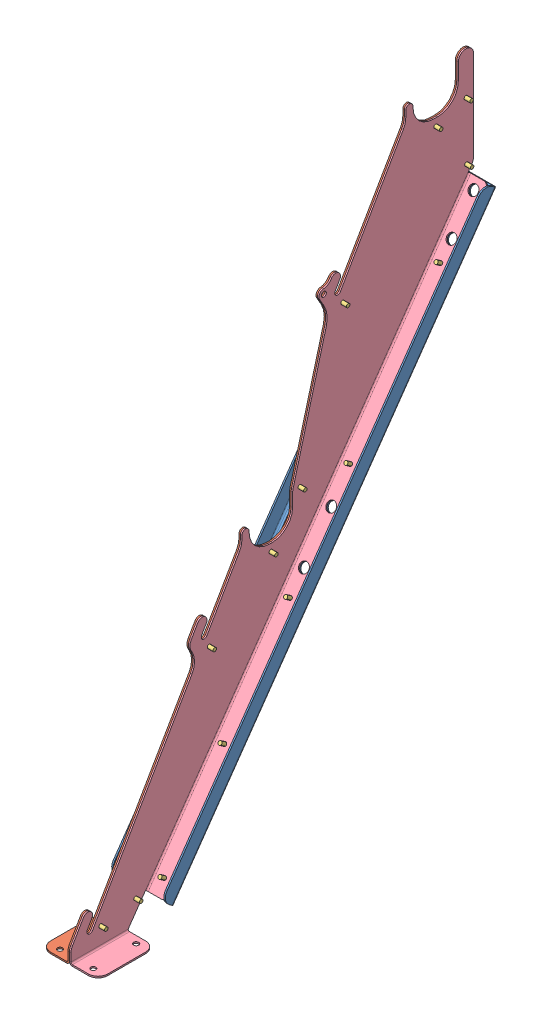
SolidWorks assembly GE-22352, configuration Default. Lengths in mm.
Overall size (76.2 794.54 536.39).
22 component instances, 4 part files, 13 mates.
Components (placement in the parent):
- GE-22352-03-1: GE-22352-03 [Default] at (0 34.7235 -102.5797) x (1 0 0) z (0 0.573576 0.819152) size (71.44 749.3 21.03)
- GE-22352-01-2: GE-22352-01 [GE-22352-01] at (-1.9844 3.9688 -76.2) x (-1 0 0) z (0 0 -1) size (38.1 794.54 536.39)
- rivet_.1875_.126-.25-3: rivet_.1875_.126-.25 [Default] at (-1.9844 738.1875 -526.1657) x (0 -0.615663 -0.788009) z (-1 0 0) size (10.01 10.01 13.03)
- rivet_.1875_.126-.25-4: rivet_.1875_.126-.25 [Default] at (-14.6844 402.9 -362.8021) x (-0.959679 -0.230262 0.161231) z (0 -0.573576 -0.819152) size (10.01 10.01 13.03)
- rivet_.1875_.126-.25-15: rivet_.1875_.126-.25 [Default] at (14.6844 574.5533 -482.995) x (-0.959679 -0.230262 0.161231) z (0 -0.573576 -0.819152) size (10.01 10.01 13.03)
- rivet_.1875_.126-.25-18: rivet_.1875_.126-.25 [Default] at (14.6844 49.1902 -115.1318) x (-0.959679 -0.230262 0.161231) z (0 -0.573576 -0.819152) size (10.01 10.01 13.03)
- rivet_.1875_.126-.25-19: rivet_.1875_.126-.25 [Default] at (14.6844 402.9 -362.8021) x (-0.959679 -0.230262 0.161231) z (0 -0.573576 -0.819152) size (10.01 10.01 13.03)
- rivet_.1875_.126-.25-20: rivet_.1875_.126-.25 [Default] at (-14.6844 288.4645 -282.6735) x (-0.959679 -0.230262 0.161231) z (0 -0.573576 -0.819152) size (10.01 10.01 13.03)
- rivet_.1875_.126-.25-21: rivet_.1875_.126-.25 [Default] at (14.6844 288.4645 -282.6735) x (-0.959679 -0.230262 0.161231) z (0 -0.573576 -0.819152) size (10.01 10.01 13.03)
- rivet_.1875_.126-.25-22: rivet_.1875_.126-.25 [Default] at (-14.6844 163.6257 -195.2604) x (-0.959679 -0.230262 0.161231) z (0 -0.573576 -0.819152) size (10.01 10.01 13.03)
- rivet_.1875_.126-.25-23: rivet_.1875_.126-.25 [Default] at (14.6844 163.6257 -195.2604) x (-0.959679 -0.230262 0.161231) z (0 -0.573576 -0.819152) size (10.01 10.01 13.03)
- rivet_.1875_.126-.25-24: rivet_.1875_.126-.25 [Default] at (-14.6844 49.1902 -115.1318) x (-0.959679 -0.230262 0.161231) z (0 -0.573576 -0.819152) size (10.01 10.01 13.03)
- GE-22352-02-4: GE-22352-02 [GE-22352-02] at (1.9844 3.9688 -76.2) size (38.1 794.54 536.39)
- rivet_.1875_.126-.25-33: rivet_.1875_.126-.25 [Default] at (-14.6844 574.5533 -482.995) x (-0.959679 -0.230262 0.161231) z (0 -0.573576 -0.819152) size (10.01 10.01 13.03)
- rivet_.1875_.126-.25-34: rivet_.1875_.126-.25 [Default] at (-1.9844 25.9658 -39.5735) x (0 -0.615663 -0.788009) z (-1 0 0) size (10.01 10.01 13.03)
- rivet_.1875_.126-.25-35: rivet_.1875_.126-.25 [Default] at (-1.9844 34.6608 -86.0629) x (0 -0.615663 -0.788009) z (-1 0 0) size (10.01 10.01 13.03)
- rivet_.1875_.126-.25-36: rivet_.1875_.126-.25 [Default] at (-1.9844 276.1822 -184.036) x (0 -0.615663 -0.788009) z (-1 0 0) size (10.01 10.01 13.03)
- rivet_.1875_.126-.25-37: rivet_.1875_.126-.25 [Default] at (-1.9844 344.4875 -266.3031) x (0 -0.615663 -0.788009) z (-1 0 0) size (10.01 10.01 13.03)
- rivet_.1875_.126-.25-38: rivet_.1875_.126-.25 [Default] at (-1.9844 400.05 -304.8) x (0 -0.615663 -0.788009) z (-1 0 0) size (10.01 10.01 13.03)
- rivet_.1875_.126-.25-39: rivet_.1875_.126-.25 [Default] at (-1.9844 584.1408 -361.836) x (0 -0.615663 -0.788009) z (-1 0 0) size (10.01 10.01 13.03)
- rivet_.1875_.126-.25-40: rivet_.1875_.126-.25 [Default] at (-1.9844 661.1938 -526.8689) x (0 -0.615663 -0.788009) z (-1 0 0) size (10.01 10.01 13.03)
- rivet_.1875_.126-.25-41: rivet_.1875_.126-.25 [Default] at (-1.9844 725.4875 -485.775) x (0 -0.615663 -0.788009) z (-1 0 0) size (10.01 10.01 13.03)
Mates (geometry in assembly coordinates):
- Concentric61: concentric aligned: cylinder of updated low funnel vertical_leftright-2 through (-1.9844 738.1875 -526.1657) axis (-1 0 0) radius 2.4574; cylinder of rivet_.1875_.126-.25-3 through (9.4456 738.1875 -526.1657) axis (-1 0 0) radius 2.3813
- Coincident41: coincident anti-aligned: plane of updated low funnel vertical_leftright-2 through (-1.9844 3.9688 -76.2) normal (-1 0 0); plane of rivet_.1875_.126-.25-3 through (-1.9844 738.1875 -526.1657) normal (1 0 0)
- Concentric71: concentric aligned: cylinder of rivet_.1875_.126-.25-4 through (-14.6844 409.456 -353.4392) axis (0 -0.573576 -0.819152) radius 2.3813; cylinder of Low Funnel Vertical_Backing-1 through (-14.6844 402.9 -362.8021) axis (0 -0.573576 -0.819152) radius 2.4574
- Coincident51: coincident anti-aligned: plane of Low Funnel Vertical_Backing-1; plane of rivet_.1875_.126-.25-4
- Concentric78: concentric aligned: cylinder of Low Funnel Vertical_Backing-1 through (-14.6844 596.498 -495.9384) axis (0 0.573576 0.819152) radius 6.35; cylinder of updated low funnel vertical_leftright-2 through (-14.6844 597.6362 -494.3129) axis (0 0.573576 0.819152) radius 6.35
- Coincident54: coincident anti-aligned: plane of Low Funnel Vertical_Backing-1; plane of updated low funnel vertical_leftright-2
- Concentric80: concentric aligned: cylinder of updated low funnel vertical_leftright-2 through (-14.6844 639.2491 -523.4506) axis (0 0.573576 0.819152) radius 6.35; cylinder of Low Funnel Vertical_Backing-1 through (-14.6844 638.1109 -525.0761) axis (0 0.573576 0.819152) radius 6.35
- Coincident55: coincident anti-aligned: plane of GE-22352-01-2 through (-1.9844 0 -76.2) normal (0 -1 0)
- Coincident56: coincident aligned: plane of GE-22352-02-4 through (0 3.9688 0) normal (0 0 1)
- Coincident57: coincident: line of GE-22352-01-2 through (0 3.9688 0) axis (0 1 0)
- Coincident58: coincident anti-aligned: plane of GE-22352-02-4 through (1.9844 0 -76.2) normal (0 -1 0)
- Coincident59: coincident: line of GE-22352-02-4 through (0 3.9688 0) axis (0 1 0)
- Concentric81: concentric anti-aligned: cylinder of GE-22352-01-2 through (-1.9844 605.9613 -336.8558) axis (-1 0 0) radius 3.3782; cylinder of GE-22352-02-4 through (1.9844 605.9613 -336.8558) axis (1 0 0) radius 3.3782
